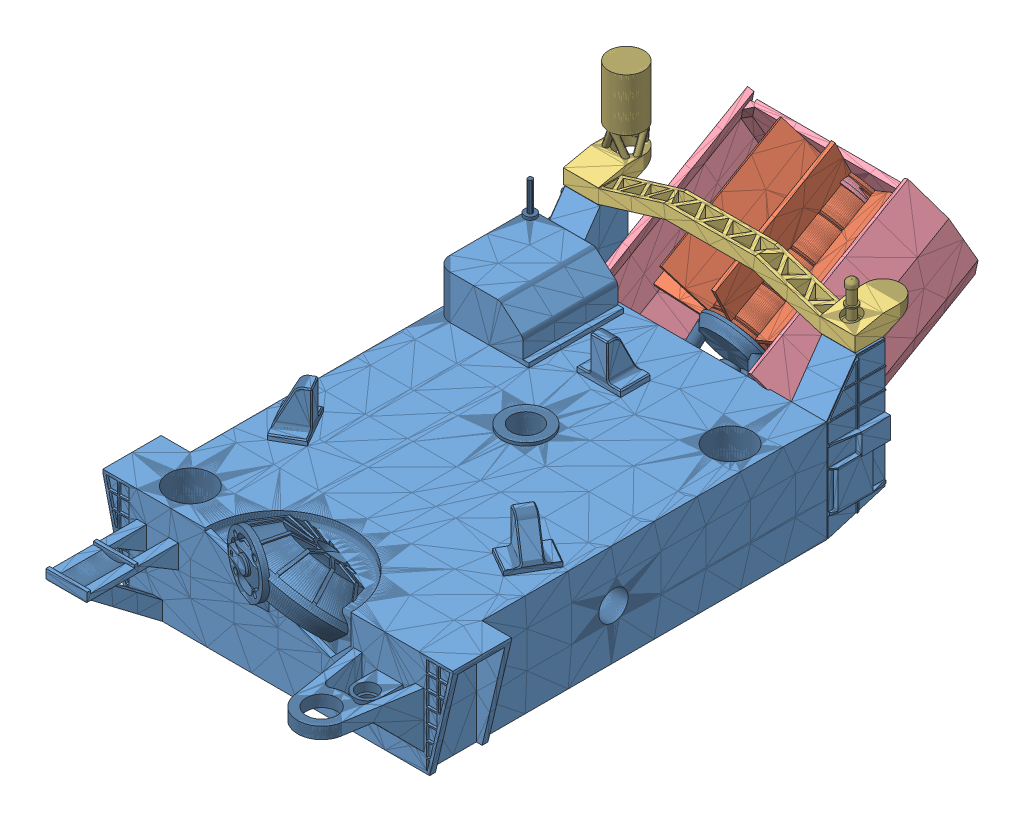
SolidWorks assembly Perserverance assembly, configuration Default. Lengths in mm.
Overall size (120 90.27 249.26).
4 component instances, 4 part files, 3 mates.
Components (placement in the parent):
- chassis-1: chassis [Default] at (77.823 73.3845 161.4894) size (120 61 208.53)
- rtg-1: rtg [Default] at (78.4167 110.3737 57.7078) x (-0.812856 -0.504428 -0.291235) z (-0.582465 0.703952 0.406431) size (55 47.5 55)
- rtg_bridge-1: rtg_bridge [Default] at (77.1448 43.3845 163.3895) size (100 32 21.59)
- rtg_shroud-1: rtg_shroud [Default] at (77.8373 108.6058 63.3988) x (1 0 0) z (0 0.866023 0.500004) size (70 62 45.98)
Mates (geometry in assembly coordinates):
- Coincident4: coincident anti-aligned: plane of chassis-1 through (77.823 115.4145 88.6919) normal (0 0.500004 -0.866023); plane of rtg-1 through (78.4167 98.2174 78.763) normal (0 -0.500004 0.866023)
- Coincident5: coincident anti-aligned: plane of chassis-1 through (77.823 123.2538 161.4894) normal (0 1 0); plane of rtg_bridge-1 through (77.1448 123.2538 163.3895) normal (0 -1 0)
- Coincident6: coincident anti-aligned: plane of rtg-1 through (78.4167 121.9676 37.6269) normal (0 0.500004 -0.866023); plane of rtg_shroud-1 through (77.8373 123.1059 38.2841) normal (0 -0.500004 0.866023)
